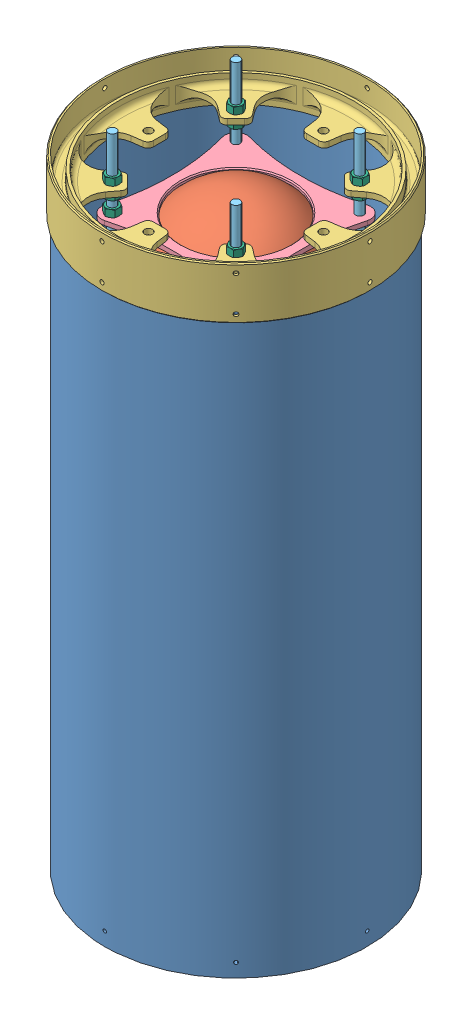
SolidWorks assembly inert_gas_assm, configuration Default. Lengths in mm.
Overall size (323.29 744.54 323.29).
32 component instances, 13 part files, 42 mates.
Components (placement in the parent):
- inert_gas_section-1: inert_gas_section [Default] at (51.0551 -12.216 653.0339) size (304.8 685.8 304.8)
- AIRTANKSFORSALE_GREAT_WHITE-1: AIRTANKSFORSALE_GREAT_WHITE [Default] at (51.0551 673.164 653.0339) x (0.983515 0 -0.180827) z (-0.180827 0 -0.983515) size (175.26 546.1 175.26)
- 000131-R01_RECOVERY_BULKHEAD-1: 000131-R01_RECOVERY_BULKHEAD [Default] at (51.0551 678.3465 653.0339) size (311.15 60.32 311.15)
- inert_gas_holder_thing-1: inert_gas_holder_thing [Default] at (51.0551 163.1564 653.0339) x (-0.707107 0 -0.707107) z (0.707107 0 -0.707107) size (228.6 5.08 228.6)
- inert_gas_holder_thing-2: inert_gas_holder_thing [Default] at (51.0551 644.6915 653.0339) x (0.707107 0 0.707107) z (-0.707107 0 0.707107) size (228.6 5.08 228.6)
- MCMASTER_94435A523-12: MCMASTER_94435A523 [Default] at (-20.7869 122.7215 724.8759) x (0 1 0) z (0.957954 0 -0.286923) size (609.6 9.53 9.53)
- MCMASTER_90670A031_ALUMINUM HEX NUT-1: MCMASTER_90670A031_ALUMINUM HEX NUT [90670A031] at (-20.7869 671.0043 724.8759) x (1 0 0) z (0 -1 0) size (14.29 16.5 9.57)
- MCMASTER_90670A031_ALUMINUM HEX NUT-2: MCMASTER_90670A031_ALUMINUM HEX NUT [90670A031] at (-20.7869 685.6887 724.8759) x (1 0 0) z (0 1 0) size (14.29 16.5 9.57)
- MCMASTER_90670A031_ALUMINUM HEX NUT-3: MCMASTER_90670A031_ALUMINUM HEX NUT [90670A031] at (-20.7869 653.9387 724.8759) x (1 0 0) z (0 1 0) size (14.29 16.5 9.57)
- MCMASTER_90670A031_ALUMINUM HEX NUT-4: MCMASTER_90670A031_ALUMINUM HEX NUT [90670A031] at (-20.7869 158.9892 724.8759) x (0.633683 0 -0.773593) z (0 1 0) size (14.29 16.5 9.57)
- MCMASTER_90670A031_ALUMINUM HEX NUT-5: MCMASTER_90670A031_ALUMINUM HEX NUT [90670A031] at (122.8972 158.9892 724.8759) x (-0.773593 0 -0.633683) z (0 1 0) size (14.29 16.5 9.57)
- MCMASTER_90670A031_ALUMINUM HEX NUT-6: MCMASTER_90670A031_ALUMINUM HEX NUT [90670A031] at (122.8972 158.9892 581.1918) x (-0.633683 0 0.773593) z (0 1 0) size (14.29 16.5 9.57)
- MCMASTER_90670A031_ALUMINUM HEX NUT-7: MCMASTER_90670A031_ALUMINUM HEX NUT [90670A031] at (-20.7869 158.9892 581.1918) x (0.773593 0 0.633683) z (0 1 0) size (14.29 16.5 9.57)
- MCMASTER_90670A031_ALUMINUM HEX NUT-8: MCMASTER_90670A031_ALUMINUM HEX NUT [90670A031] at (122.8972 685.6887 724.8759) x (0 0 -1) z (0 1 0) size (14.29 16.5 9.57)
- MCMASTER_90670A031_ALUMINUM HEX NUT-9: MCMASTER_90670A031_ALUMINUM HEX NUT [90670A031] at (122.8972 685.6887 581.1918) x (-1 0 0) z (0 1 0) size (14.29 16.5 9.57)
- MCMASTER_90670A031_ALUMINUM HEX NUT-10: MCMASTER_90670A031_ALUMINUM HEX NUT [90670A031] at (-20.7869 685.6887 581.1918) x (0 0 1) z (0 1 0) size (14.29 16.5 9.57)
- MCMASTER_90670A031_ALUMINUM HEX NUT-11: MCMASTER_90670A031_ALUMINUM HEX NUT [90670A031] at (122.8972 671.0043 724.8759) x (0 0 -1) z (0 -1 0) size (14.29 16.5 9.57)
- MCMASTER_90670A031_ALUMINUM HEX NUT-12: MCMASTER_90670A031_ALUMINUM HEX NUT [90670A031] at (122.8972 671.0043 581.1918) x (-1 0 0) z (0 -1 0) size (14.29 16.5 9.57)
- MCMASTER_90670A031_ALUMINUM HEX NUT-13: MCMASTER_90670A031_ALUMINUM HEX NUT [90670A031] at (-20.7869 671.0043 581.1918) x (0 0 1) z (0 -1 0) size (14.29 16.5 9.57)
- MCMASTER_94435A523-13: MCMASTER_94435A523 [Default] at (122.8972 122.7215 724.8759) x (0 1 0) z (-0.286923 0 -0.957954) size (609.6 9.53 9.53)
- MCMASTER_94435A523-14: MCMASTER_94435A523 [Default] at (122.8972 122.7215 581.1918) x (0 1 0) z (-0.957954 0 0.286923) size (609.6 9.53 9.53)
- MCMASTER_94435A523-15: MCMASTER_94435A523 [Default] at (-20.7869 122.7215 581.1918) x (0 1 0) z (0.286923 0 0.957954) size (609.6 9.53 9.53)
- KPF1LWA8C8P30000_3D-1: KPF1LWA8C8P30000_3D [Default] at (-44.6859 91.7539 697.7919) x (-0.943171 0 -0.332308) z (0.332308 0 -0.943171) size (80 80 124.46)
- RV2MF-8N-S316-1: RV2MF-8N-S316 [Default] at (77.4519 91.7539 578.1134) x (0.332308 0 -0.943171) z (0 -1 0) size (53.07 103.88 27.09)
  - RV1-MF-8N-BODY-1: RV1-MF-8N-BODY [Default] at origin size (53.07 103.88 27.09)
- 51205K175_EXTREME-PRESSURE 316 SS THREADED PIPE FITTING-1: 51205K175_EXTREME-PRESSURE 316 SS THREADED PIPE FITTING [51205K175] at (51.0551 91.7539 653.0339) x (0.332308 0 -0.943171) z (0.943171 0 0.332308) size (63.86 63.86 31.16)
- 4548K173_STD-WALL TYPE 316-316L SS THRD PIPE NIPPLE-2: 4548K173_STD-WALL TYPE 316-316L SS THRD PIPE NIPPLE [4548K173] at (63.1307 91.7539 618.7606) x (0.332308 0 -0.943171) z (0.942905 -0.023727 0.332215) size (50.97 22.35 22.37)
- 51205K115_EXTREME-PRESSURE 316 SS THREADED PIPE FITTING-1: 51205K115_EXTREME-PRESSURE 316 SS THREADED PIPE FITTING [51205K115] at (51.0551 42.9859 653.0339) x (0.825025 0 0.565096) z (-0.565096 0 0.825025) size (50.93 50.93 23.11)
- KPF1LWA8C8P30000_3D-2: KPF1LWA8C8P30000_3D [Default] at (80.0807 43.0008 702.6108) x (0.825025 0 0.565096) z (0.565096 -0.000611 -0.825025) size (80 80 124.46)
- 48805K195_PRECISION EXTREME-PRESSURE 316SS PIPE FITTING-1: 48805K195_PRECISION EXTREME-PRESSURE 316SS PIPE FITTING [48805K195] at (34.5959 91.7539 699.7491) x (-0.332308 0 0.943171) z (0 1 0) size (53.03 63.43 31.16)
- 4548K173_STD-WALL TYPE 316-316L SS THRD PIPE NIPPLE-3: 4548K173_STD-WALL TYPE 316-316L SS THRD PIPE NIPPLE [4548K173] at (0.3227 91.7539 687.6736) x (-0.943171 0 -0.332308) z (0.332215 -0.023727 -0.942905) size (50.97 22.35 22.37)
- TE_M5200-1: TE_M5200 [Default] at (58.0733 91.7539 708.0209) x (0.14352 -0.901928 -0.407344) z (-0.299718 -0.431887 0.850672) size (25.4 54.61 25.4)
Mates (geometry in assembly coordinates):
- Concentric17: concentric anti-aligned: cylinder of inert_gas_section-1 through (51.0551 673.584 653.0339) axis (0 -1 0) radius 152.4; cylinder of AIRTANKSFORSALE_GREAT_WHITE-1 through (51.0551 139.764 653.0339) axis (0 1 0) radius 87.63
- Concentric22: concentric anti-aligned: cylinder of inert_gas_section-1 through (51.0551 673.584 653.0339) axis (0 -1 0) radius 152.4; cylinder of 000131-R01_RECOVERY_BULKHEAD-1 through (51.0551 722.8129 653.0339) axis (0 1 0) radius 155.575
- Concentric23: concentric aligned: cylinder of inert_gas_section-1 through (-101.3449 657.709 653.0339) axis (-1 0 0) radius 2.0193; cylinder of 000131-R01_RECOVERY_BULKHEAD-1 through (-104.5199 657.709 653.0339) axis (-1 0 0) radius 2.4574
- Distance3: distance = 25.4 mm anti-aligned: plane of inert_gas_holder_thing-2 through (51.0551 649.7715 653.0339) normal (0 1 0); plane of 000131-R01_RECOVERY_BULKHEAD-1 through (51.0551 675.1715 653.0339) normal (0 -1 0)
- Tangent7: tangent aligned: sphere of AIRTANKSFORSALE_GREAT_WHITE-1; cone of inert_gas_holder_thing-1 through (51.0551 166.9664 653.0339) axis (0 -1 0)
- Tangent8: tangent aligned: sphere of AIRTANKSFORSALE_GREAT_WHITE-1; cone of inert_gas_holder_thing-2 through (51.0551 644.6915 653.0339) axis (0 1 0)
- Distance4: distance = 50.8 mm aligned: plane of MCMASTER_94435A523-12 through (-20.7869 732.3215 724.8759) normal (0 1 0); plane of 000131-R01_RECOVERY_BULKHEAD-1 through (51.0551 681.5215 653.0339) normal (0 1 0)
- Concentric25: concentric anti-aligned: cylinder of MCMASTER_94435A523-12 through (-20.7869 732.3215 724.8759) axis (0 -1 0) radius 4.7625; circle of MCMASTER_90670A031_ALUMINUM HEX NUT-4
- Coincident9: coincident anti-aligned: plane of inert_gas_holder_thing-2 through (51.0551 649.7715 653.0339) normal (0 1 0); plane of MCMASTER_90670A031_ALUMINUM HEX NUT-3 through (-27.9307 649.7715 720.7515) normal (0 -1 0)
- Coincident10: coincident anti-aligned: plane of 000131-R01_RECOVERY_BULKHEAD-1 through (51.0551 681.5215 653.0339) normal (0 1 0); plane of MCMASTER_90670A031_ALUMINUM HEX NUT-2 through (-27.9307 681.5215 720.7515) normal (0 -1 0)
- Coincident11: coincident anti-aligned: plane of 000131-R01_RECOVERY_BULKHEAD-1 through (51.0551 675.1715 653.0339) normal (0 -1 0); plane of MCMASTER_90670A031_ALUMINUM HEX NUT-1 through (-27.9307 675.1715 729.0004) normal (0 1 0)
- Concentric24: concentric anti-aligned: cylinder of MCMASTER_94435A523-12 through (-20.7869 732.3215 724.8759) axis (0 -1 0) radius 4.7625; circle of MCMASTER_90670A031_ALUMINUM HEX NUT-3
- Coincident13: coincident anti-aligned: cylinder of MCMASTER_94435A523-12 through (-20.7869 732.3215 724.8759) axis (0 -1 0) radius 4.7625; circle of MCMASTER_90670A031_ALUMINUM HEX NUT-2
- Coincident14: coincident aligned: cylinder of MCMASTER_94435A523-12 through (-20.7869 732.3215 724.8759) axis (0 -1 0) radius 4.7625; circle of MCMASTER_90670A031_ALUMINUM HEX NUT-1
- Coincident15: coincident anti-aligned: plane of inert_gas_holder_thing-1 through (51.0551 163.1564 653.0339) normal (0 -1 0); plane of MCMASTER_90670A031_ALUMINUM HEX NUT-4 through (-28.5044 163.1564 727.7887) normal (0 1 0)
- Concentric26: concentric aligned: cylinder of 000131-R01_RECOVERY_BULKHEAD-1 through (-20.7869 681.5215 724.8759) axis (0 1 0) radius 4.7625; cylinder of inert_gas_holder_thing-2 through (-20.7869 649.7715 724.8759) axis (0 1 0) radius 4.7625
- Concentric27: concentric aligned: cylinder of 000131-R01_RECOVERY_BULKHEAD-1 through (-20.7869 681.5215 581.1918) axis (0 1 0) radius 4.7625; cylinder of inert_gas_holder_thing-2 through (-20.7869 649.7715 581.1918) axis (0 1 0) radius 4.7625
- Concentric28: concentric anti-aligned: cylinder of 000131-R01_RECOVERY_BULKHEAD-1 through (-20.7869 681.5215 724.8759) axis (0 1 0) radius 4.7625; cylinder of MCMASTER_94435A523-12 through (-20.7869 732.3215 724.8759) axis (0 -1 0) radius 4.7625
- Concentric29: concentric aligned: cylinder of AIRTANKSFORSALE_GREAT_WHITE-1 through (51.0551 500673.164 653.0339) axis (0 -1 0) radius 9.525; cylinder of 51205K175_EXTREME-PRESSURE 316 SS THREADED PIPE FITTING-1 through (51.0551 122.9959 653.0339) axis (0 -1 0) radius 15.5812
- Concentric30: concentric anti-aligned: cylinder of inert_gas_holder_thing-1 through (-20.7869 168.2364 581.1918) axis (0 1 0) radius 4.7625; cylinder of MCMASTER_94435A523-15 through (-20.7869 732.3215 581.1918) axis (0 -1 0) radius 4.7625
- Concentric31: concentric anti-aligned: cylinder of inert_gas_holder_thing-1 through (-20.7869 168.2364 724.8759) axis (0 1 0) radius 4.7625; cylinder of MCMASTER_94435A523-12 through (-20.7869 732.3215 724.8759) axis (0 -1 0) radius 4.7625
- Concentric43: concentric anti-aligned: cylinder of 51205K175_EXTREME-PRESSURE 316 SS THREADED PIPE FITTING-1 through (61.4371 91.7539 623.5673) axis (-0.332308 0 0.943171) radius 15.5812; cylinder of 4548K173_STD-WALL TYPE 316-316L SS THRD PIPE NIPPLE-2 through (63.1307 91.7539 618.7606) axis (0.332308 0 -0.943171) radius 10.668
- Concentric45: concentric anti-aligned: cylinder of RV2MF-8N-S316-1/RV1-MF-8N-BODY-1 through (78.0833 91.7539 576.3214) axis (-0.332308 0 0.943171) radius 8.8011; cylinder of 4548K173_STD-WALL TYPE 316-316L SS THRD PIPE NIPPLE-2 through (63.1307 91.7539 618.7606) axis (0.332308 0 -0.943171) radius 10.668
- Coincident30: coincident anti-aligned: plane of RV2MF-8N-S316-1/RV1-MF-8N-BODY-1 through (64.8242 91.7539 613.9539) normal (-0.332308 0 0.943171); circle of 4548K173_STD-WALL TYPE 316-316L SS THRD PIPE NIPPLE-2
- Coincident31: coincident aligned: plane of 51205K175_EXTREME-PRESSURE 316 SS THREADED PIPE FITTING-1 through (61.4371 91.7539 623.5673) normal (0.332308 0 -0.943171); circle of 4548K173_STD-WALL TYPE 316-316L SS THRD PIPE NIPPLE-2
- Coincident35: coincident anti-aligned: plane of 51205K175_EXTREME-PRESSURE 316 SS THREADED PIPE FITTING-1 through (51.0551 60.5119 653.0339) normal (0 -1 0); plane of 51205K115_EXTREME-PRESSURE 316 SS THREADED PIPE FITTING-1 through (50.0687 60.5119 665.8275) normal (0 1 0)
- Concentric49: concentric anti-aligned: cylinder of 51205K175_EXTREME-PRESSURE 316 SS THREADED PIPE FITTING-1 through (51.0551 73.9739 653.0339) axis (0 1 0) radius 8.001; cylinder of 51205K115_EXTREME-PRESSURE 316 SS THREADED PIPE FITTING-1 through (51.0551 80.3239 653.0339) axis (0 -1 0) radius 7.8289
- Concentric50: concentric anti-aligned: cylinder of 51205K115_EXTREME-PRESSURE 316 SS THREADED PIPE FITTING-1 through (81.8599 42.9859 674.1334) axis (-0.825025 0 -0.565096) radius 7.8289; cone of KPF1LWA8C8P30000_3D-2 through (67.0338 42.9859 663.9784) axis (0.825025 0 0.565096)
- Angle1: planar angle = 1.308997 rad anti-aligned: plane of 51205K115_EXTREME-PRESSURE 316 SS THREADED PIPE FITTING-1 through (64.5645 51.7489 648.8177) normal (0.565096 0 -0.825025); plane of 51205K175_EXTREME-PRESSURE 316 SS THREADED PIPE FITTING-1 through (42.2215 80.0381 637.4998) normal (-0.943171 0 -0.332308)
- Coincident39: coincident: circle of 51205K115_EXTREME-PRESSURE 316 SS THREADED PIPE FITTING-1; cone of KPF1LWA8C8P30000_3D-2 through (65.4527 42.9859 662.8954) axis (0.825025 0 0.565096)
- Parallel6: parallel aligned: plane of RV2MF-8N-S316-1/RV1-MF-8N-BODY-1 through (51.6198 109.3515 609.3016) normal (-0.943171 0 -0.332308); plane of 51205K175_EXTREME-PRESSURE 316 SS THREADED PIPE FITTING-1 through (42.2215 80.0381 637.4998) normal (-0.943171 0 -0.332308)
- Concentric51: concentric anti-aligned: cylinder of 51205K175_EXTREME-PRESSURE 316 SS THREADED PIPE FITTING-1 through (56.9636 91.7539 636.2643) axis (-0.332308 0 0.943171) radius 8.001; cylinder of 48805K195_PRECISION EXTREME-PRESSURE 316SS PIPE FITTING-1 through (34.5959 91.7539 699.7491) axis (0.332308 0 -0.943171) radius 6.35
- Angle2: planar angle = 1.570796 rad aligned: plane of 48805K195_PRECISION EXTREME-PRESSURE 316SS PIPE FITTING-1 through (34.5959 105.2476 699.7491) normal (0 1 0); plane of 51205K175_EXTREME-PRESSURE 316 SS THREADED PIPE FITTING-1 through (42.2215 80.0381 637.4998) normal (-0.943171 0 -0.332308)
- Concentric52: concentric aligned: cone of KPF1LWA8C8P30000_3D-1 through (-5.8017 91.7539 685.5158) axis (-0.943171 0 -0.332308); cylinder of 48805K195_PRECISION EXTREME-PRESSURE 316SS PIPE FITTING-1 through (55.2697 91.7539 707.0331) axis (-0.943171 0 -0.332308) radius 6.35
- Coincident41: coincident anti-aligned: plane of 51205K175_EXTREME-PRESSURE 316 SS THREADED PIPE FITTING-1 through (40.6732 91.7539 682.5004) normal (-0.332308 0 0.943171); plane of 48805K195_PRECISION EXTREME-PRESSURE 316SS PIPE FITTING-1 through (40.6732 118.7414 682.5004) normal (0.332308 0 -0.943171)
- Concentric53: concentric aligned: cone of KPF1LWA8C8P30000_3D-1 through (-5.8017 91.7539 685.5158) axis (-0.943171 0 -0.332308); cylinder of 4548K173_STD-WALL TYPE 316-316L SS THRD PIPE NIPPLE-3 through (0.3227 91.7539 687.6736) axis (-0.943171 0 -0.332308) radius 10.668
- Concentric54: concentric aligned: cylinder of 48805K195_PRECISION EXTREME-PRESSURE 316SS PIPE FITTING-1 through (55.2697 91.7539 707.0331) axis (-0.943171 0 -0.332308) radius 6.35; cylinder of 4548K173_STD-WALL TYPE 316-316L SS THRD PIPE NIPPLE-3 through (0.3227 91.7539 687.6736) axis (-0.943171 0 -0.332308) radius 10.668
- Coincident42: coincident: cone of KPF1LWA8C8P30000_3D-1 through (-3.9941 91.7539 686.1527) axis (-0.943171 0 -0.332308); circle of 4548K173_STD-WALL TYPE 316-316L SS THRD PIPE NIPPLE-3
- Coincident43: coincident aligned: plane of 48805K195_PRECISION EXTREME-PRESSURE 316SS PIPE FITTING-1 through (5.1294 91.7539 689.3672) normal (-0.943171 0 -0.332308); circle of 4548K173_STD-WALL TYPE 316-316L SS THRD PIPE NIPPLE-3
- Concentric55: concentric aligned: cylinder of 48805K195_PRECISION EXTREME-PRESSURE 316SS PIPE FITTING-1 through (55.2697 91.7539 707.0331) axis (-0.943171 0 -0.332308) radius 6.35; cylinder of TE_M5200-1 through (58.0733 91.7539 708.0209) axis (-0.943171 0 -0.332308) radius 8.89
- Distance5: distance = 2.54 mm anti-aligned: plane of TE_M5200-1 through (68.2808 80.2994 705.8019) normal (-0.943171 0 -0.332308); plane of 48805K195_PRECISION EXTREME-PRESSURE 316SS PIPE FITTING-1 through (64.0625 91.7539 710.1311) normal (0.943171 0 0.332308)
- Parallel7: parallel aligned: plane of KPF1LWA8C8P30000_3D-1 through (-43.5228 109.2539 694.4908) normal (0 1 0); plane of 48805K195_PRECISION EXTREME-PRESSURE 316SS PIPE FITTING-1 through (34.5959 105.2476 699.7491) normal (0 1 0)
